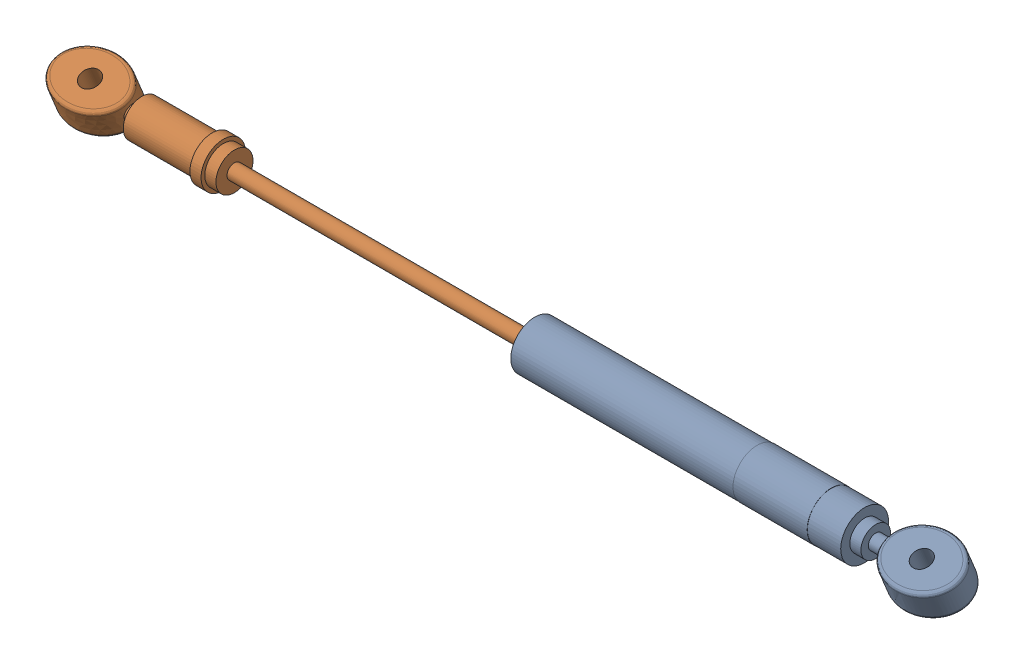
SolidWorks assembly 24-SU-40-006, configuration Default. Lengths in mm.
Overall size (246.08 18.71 21.17).
2 component instances, 2 part files, 7 mates.
Components (placement in the parent):
- 24-SU-40-004-1: 24-SU-40-004 [Default] at (14.8283 -25.5099 -30.3788) x (1 0 0) z (0 0.924225 0.381849) size (117.73 17.54 13)
- 24-SU-40-005-1: 24-SU-40-005 [Default] at (-132.1864 -25.5099 -30.3788) x (0 0.924225 0.381849) z (-1 0 0) size (12 16.69 155.33)
Mates (geometry in assembly coordinates):
- Concentric4: concentric aligned: cylinder of 23-SU-40-004-1 through (-35.1717 -25.5099 -30.3788) axis (-1 0 0) radius 2; cylinder of 23-SU-40-005-1 through (-19.1864 -25.5099 -30.3788) axis (-1 0 0) radius 2
- Concentric5: concentric aligned: circle of 23-SU-40-002-1; circle of 23-SU-40-005-1
- Coincident2: coincident anti-aligned: plane of 23-SU-40-002-1 through (-121.7165 -23.6614 -29.6151) normal (0 -0.924225 -0.381849); plane of 23-SU-40-005-1 through (-163.6699 -21.813 -28.8514) normal (0 0.924225 0.381849)
- Parallel1: parallel aligned: plane of 23-SU-40-004-1 through (60.788 -29.2068 -31.9062) normal (0 -0.924225 -0.381849); plane of 23-SU-40-005-1 through (-163.6699 -29.2068 -31.9062) normal (0 -0.924225 -0.381849)
- LimitDistance2: limit distance = 38.1 mm anti-aligned: plane of 23-SU-40-005-1 through (-126.1864 -25.5099 -30.3788) normal (1 0 0); plane of 23-SU-40-004-1 through (-46.1717 -25.5099 -30.3788) normal (-1 0 0)
- Concentric6: concentric aligned: circle of 23-SU-40-004-1; cylinder of 23-SU-40-007-1 through (60.788 -23.6614 -29.6151) axis (0 0.924225 0.381849) radius 2.5006
- Coincident3: coincident anti-aligned: plane of 23-SU-40-004-1 through (60.788 -21.813 -28.8514) normal (0 0.924225 0.381849); plane of 23-SU-40-007-1 through (60.788 -23.6614 -29.6151) normal (0 -0.924225 -0.381849)
